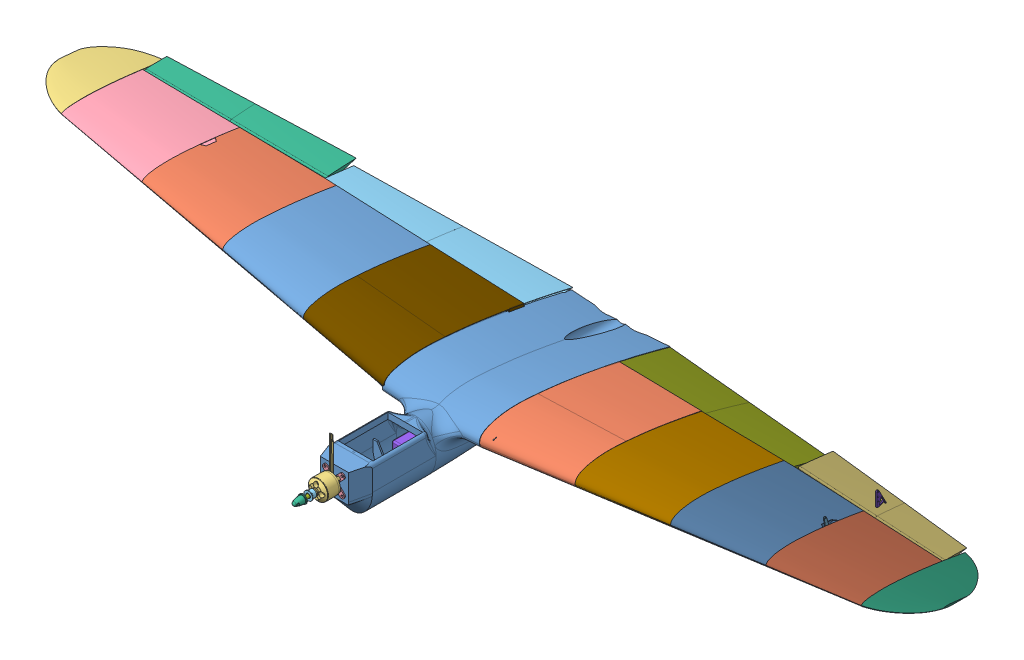
SolidWorks assembly assemtest1, configuration Default. Lengths in mm.
Overall size (1260.17 263.99 1096.25).
27 component instances, 24 part files, 6 mates.
Components (placement in the parent):
- fuselage_3-1: fuselage_3 [Default] at (269.5426 576.6289 1265.5177) size (516.5 263.99 1038.57)
- holes_sec1-1: holes_sec1 [Default] at (338.3476 600.7438 1224.1735) x (0.999507 -0.031406 0.000548) z (0 0.017452 0.999848) size (139.88 62.18 205.01)
- BLDC_A2212_13T_1000KV_Assemly-1: BLDC_A2212_13T_1000KV_Assemly [Default] at (269.5426 590.5055 1388.6609) x (-0.002542 0.999997 0) z (0.999997 0.002542 0) size (87.69 59.44 56.76)
  - BLDC_A2212_13T_1000KV-1: BLDC_A2212_13T_1000KV [Default] at origin size (73.15 40.13 27.69)
  - BLDC_A2212_13T_1000KV_MountPlate-1: BLDC_A2212_13T_1000KV_MountPlate [Default] at (0 -26.67 0) x (-0.707107 0 -0.707107) z (-0.707107 0 0.707107) size (40.13 1.47 40.13)
  - BLDC_A2212_13T_1000KV_PropCollar-1: BLDC_A2212_13T_1000KV_PropCollar [Default] at (0 8.8646 0) x (0.997679 0 0.068095) z (0.068095 0 -0.997679) size (12.06 6.96 12.06)
  - BLDC_A2212_13T_1000KV_PropNut-1: BLDC_A2212_13T_1000KV_PropNut [Default] at (0 16.0097 0) x (-0.117252 0 0.993102) z (-0.993102 0 -0.117252) size (11.84 14.81 11.84)
  - BLDC_A2212_13T_1000KV_PropThread-1: BLDC_A2212_13T_1000KV_PropThread [Default] at (0 1.905 0) size (7.91 22.53 7.91)
- Turnigy_2200mAh_3S_20C_Lipo_Pack-1: Turnigy_2200mAh_3S_20C_Lipo_Pack [Valor predeterminado] at (257.6062 570.6464 1216.5177) x (0 0 -1) z (1 0 0) size (103 34 24)
- Left Wing Assembly version 3.0-1: Left Wing Assembly version 3.0 [Default] at (356.2911 492.0947 1012.0003) x (0.999507 -0.031401 0.000802) z (-0.000175 0.019952 0.999801) size (1257.86 91.52 276.09)
  - holes_sec1-1: holes_sec1 [Default] at (-21.1787 103.8047 214.3011) size (139.88 62.18 205.01)
  - holes_sec2-1: holes_sec2 [Default] at (-21.1787 103.8047 214.3011) size (142.86 54.4 187.37)
  - holes_sec3-1: holes_sec3 [Default] at (-21.1787 103.8047 214.3011) size (141.4 44.82 168.18)
  - holes_sec4-1: holes_sec4 [Default] at (-21.1787 103.8047 214.3011) size (133.72 34.85 144.08)
  - wang_fin2_aileron_left-1: wang_fin2_aileron_left [Default] at (-19.3474 67.6819 204.2839) x (0.999776 0.020626 -0.004663) z (0.008001 -0.164862 0.986284) size (232.68 32.44 70.02)
  - Servo Motor (SG90)-1: Servo Motor (SG90) [Default] at (369.0001 141.0439 92.2244) x (0.123302 -0.062035 -0.990428) z (0.987706 0.104311 0.11643) size (31.9 11.8 29.9)
  - Servo Control Rod-1: Servo Control Rod [Default] at (349.0307 139.3365 95.247) x (0.094489 0.19497 -0.976247) z (0.987706 0.104311 0.11643) size (5 20 3)
  - wangtip-2: wangtip [Default] at (479.0832 126.5551 183.6971) x (0.994881 0.101056 0) z (-0.003437 0.03384 0.999421) size (72.69 16.61 151.1)
  - wang_fin2_trailingedge-2: wang_fin2_trailingedge [Default] at (-21.1787 103.8047 214.3011) size (279.36 44.38 89.85)
  - Aileron_Hook_left-1: Aileron_Hook_left [Default] at (355.9995 137.0895 25.4434) x (-0.060242 0.132243 0.989385) z (-0.992737 -0.111338 -0.045564) size (16.5 21.5 15)
  - holes_sec1Mirror-2: holes_sec1Mirror [Default] at (-156.6987 103.8047 214.3011) x (-1 0 0) z (0 0 -1) size (139.88 62.18 205.01)
  - holes_sec2Mirror-2: holes_sec2Mirror [Default] at (-156.6987 103.8047 214.3011) x (-1 0 0) z (0 0 -1) size (142.86 54.4 187.37)
  - holes_sec3Mirror-2: holes_sec3Mirror [Default] at (-156.6987 103.8047 214.3011) x (-1 0 0) z (0 0 -1) size (141.4 44.82 168.18)
  - wangtipMirror-3: wangtipMirror [Default] at (-656.9606 126.5551 183.6971) x (-0.994881 0.101056 0) z (-0.003437 -0.03384 -0.999421) size (72.69 16.61 151.1)
  - holes_sec4Mirror-2: holes_sec4Mirror [Default] at (-156.6987 103.8047 214.3011) x (-1 0 0) z (0 0 -1) size (133.72 34.85 144.08)
  - wang_fin2_trailingedgeMirror-3: wang_fin2_trailingedgeMirror [Default] at (-156.6987 103.8047 214.3011) x (-1 0 0) z (0 0 -1) size (279.36 44.38 89.85)
  - wang_fin2_aileron_leftMirror-2: wang_fin2_aileron_leftMirror [Default] at (-158.53 67.6819 204.2839) x (-0.999776 0.020626 -0.004663) z (0.008001 0.164862 -0.986284) size (232.68 32.44 70.02)
Mates (geometry in assembly coordinates):
- Coincident2: coincident anti-aligned: plane of fuselage_3-1 through (269.5426 576.6289 1360.5177) normal (0 0 1); plane of BLDC_A2212_13T_1000KV_Assemly-1/BLDC_A2212_13T_1000KV_MountPlate-1 through (281.0076 602.209 1360.5177) normal (0 0 -1)
- Concentric1: concentric aligned: cylinder of fuselage_3-1 through (269.5426 590.5055 1455.5177) axis (0 0 -1) radius 10; cylinder of BLDC_A2212_13T_1000KV_Assemly-1/BLDC_A2212_13T_1000KV-1 through (269.5426 590.5055 1359.7049) axis (0 0 -1) radius 13.843
- Coincident4: coincident anti-aligned: plane of fuselage_3-1 through (269.5426 576.6289 1165.5177) normal (0 0 1); plane of Turnigy_2200mAh_3S_20C_Lipo_Pack-1 through (269.6062 576.6464 1165.5177) normal (0 0 -1)
- Lock2: lock: unknown of fuselage_3-1; unknown of holes_sec1-1
- Coincident5: coincident anti-aligned: plane of holes_sec1-1 through (463.0392 609.4846 1224.0193) normal (0.997551 0.069928 -0.001234); plane of Left Wing Assembly version 3.0-1/holes_sec2-1 through (463.0375 609.5091 1224.018) normal (-0.997551 -0.069928 0.001234)
- Coincident6: coincident: point of holes_sec1-1; point of Left Wing Assembly version 3.0-1/holes_sec2-1
